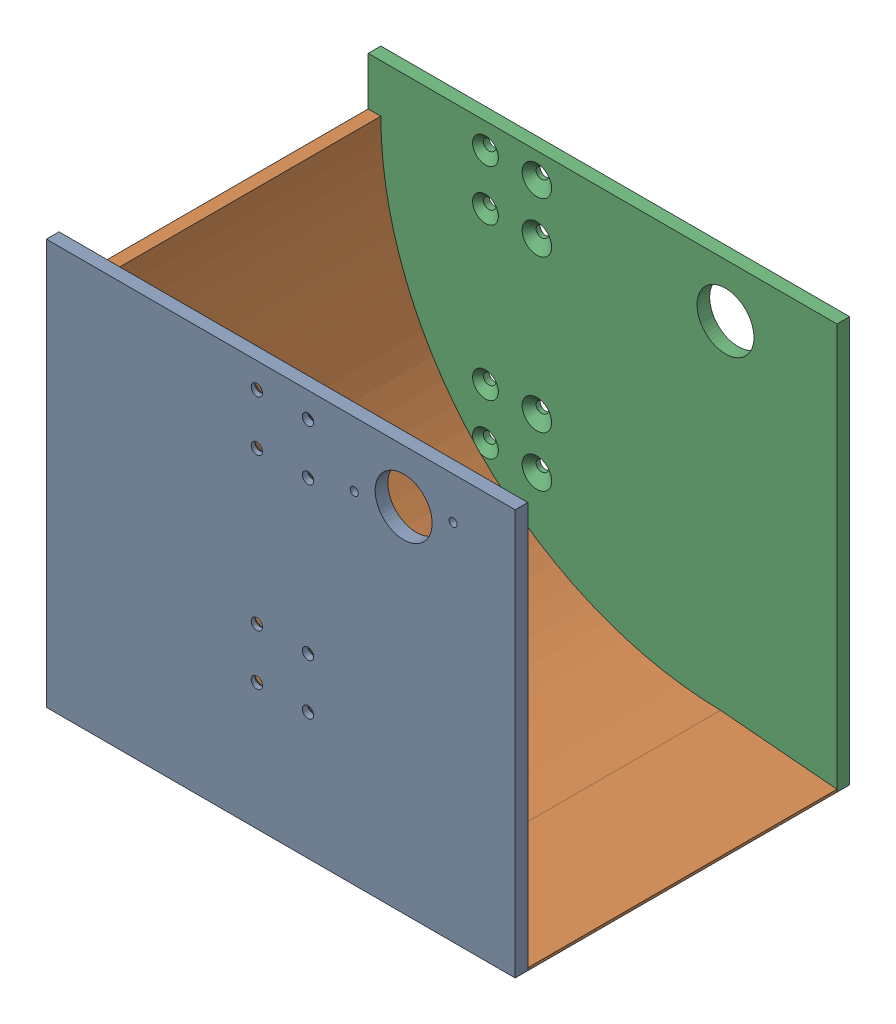
SolidWorks assembly kicker assem, configuration Default. Lengths in mm.
Overall size (234.95 203.2 167.64).
3 component instances, 3 part files, 6 mates.
Components (placement in the parent):
- Kicker side panel A-1: Kicker side panel A [Default] at (-61.595 -77.47 77.47) size (234.95 203.2 6.35)
- Kicker ramp-2: Kicker ramp [Default] at origin size (234.95 179.07 154.94)
- Kicker side panel B-2: Kicker side panel B [Default] at (-61.595 -77.47 -83.82) size (234.95 203.2 6.35)
Mates (geometry in assembly coordinates):
- Coincident5: coincident aligned: plane of Kicker side panel A-1 through (-179.07 -179.07 83.82) normal (-1 0 0); plane of Kicker side panel B-2 through (-179.07 -179.07 -77.47) normal (-1 0 0)
- Coincident6: coincident aligned: plane of Kicker side panel A-1 through (-179.07 24.13 83.82) normal (0 1 0); plane of Kicker side panel B-2 through (-179.07 24.13 -77.47) normal (0 1 0)
- Coincident11: coincident anti-aligned: plane of Kicker side panel B-2 through (-61.595 -77.47 -77.47) normal (0 0 1); plane of Kicker ramp-2 through (0 0 -77.47) normal (0 0 -1)
- Coincident12: coincident anti-aligned: plane of Kicker side panel A-1 through (-61.595 -77.47 77.47) normal (0 0 -1); plane of Kicker ramp-2 through (0 0 77.47) normal (0 0 1)
- Coincident40: coincident aligned: plane of Kicker side panel B-2 through (55.88 -179.07 -77.47) normal (1 0 0); plane of Kicker ramp-2 through (55.88 -172.72 77.47) normal (1 0 0)
- Symmetric2: symmetric aligned: plane of Kicker side panel B-2 through (-179.07 -179.07 -77.47) normal (0 -1 0); plane of Kicker ramp-2 through (55.88 -179.07 77.47) normal (0 -1 0); plane of Kicker side panel B-2 through (-61.595 -77.47 -77.47) normal (0 0 1)
